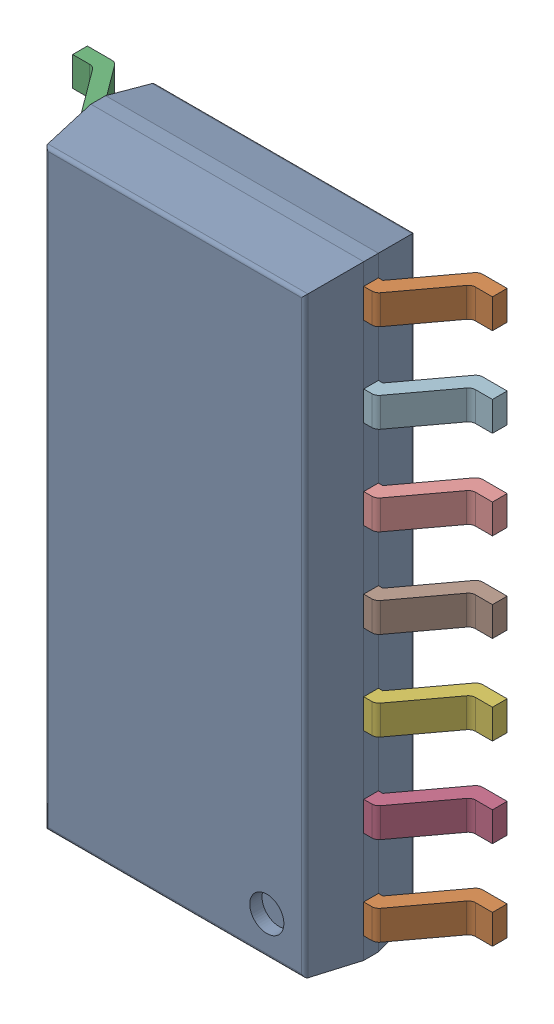
SolidWorks assembly IC11_IC102_1.step, configuration Default. Lengths in mm.
Overall size (6 8.65 1.75).
3 component instances, 2 part files, 0 mates.
Components (placement in the parent):
- 6348793888_1.step-11: 6348793888_1.step [Default] at (521.774 291.943 0) x (-1 0 0) z (0 0 1) size (6 8.65 1.75)
  - Body-16_1.step-54: Body-16_1.step [Default] at origin size (3.9 8.65 1.57)
  - PinsArrayLR-17_1.step-54: PinsArrayLR-17_1.step [Default] at origin size (6 8.04 1)
